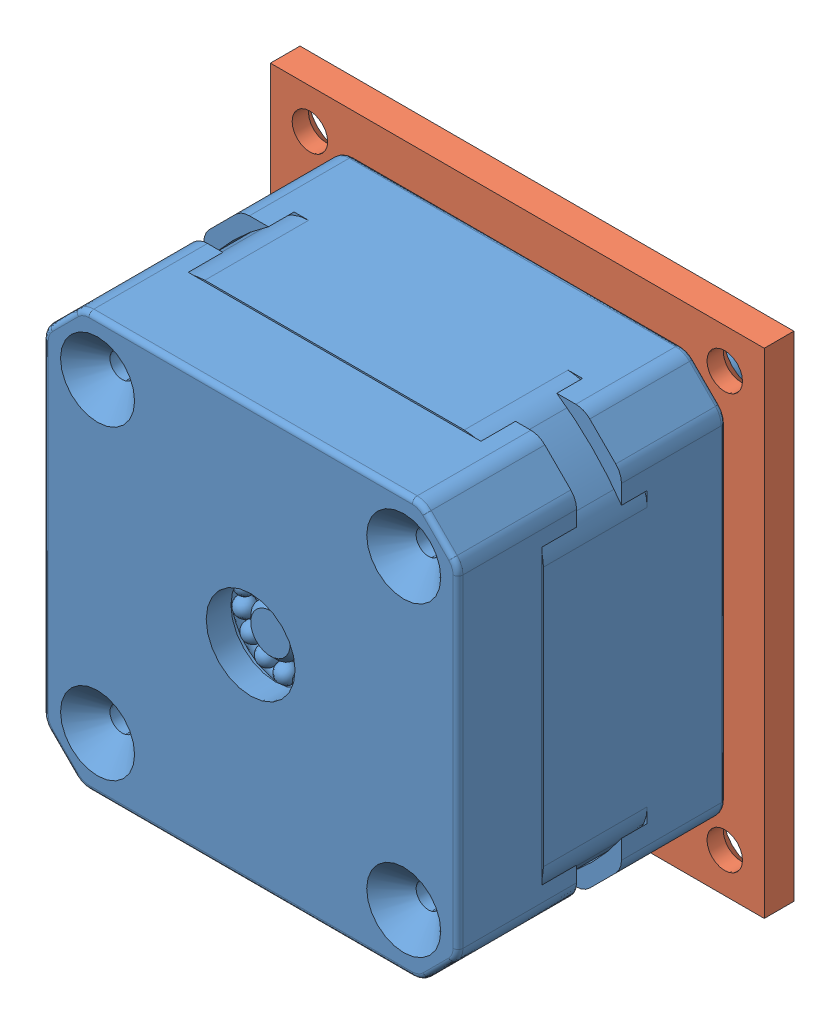
SolidWorks assembly Motor_and_plate, configuration Default. Lengths in mm.
Overall size (50 50 51.3).
2 component instances, 2 part files, 3 mates.
Components (placement in the parent):
- NEMA_17_PHB42S28-406A v2-1: NEMA_17_PHB42S28-406A v2 [Default] at (16.9071 48.8811 -1035.1401) size (42.3 42.3 51.3)
- Plate-1: Plate [Default] at (12.2071 33.8811 36.8599) x (0 -1 0) z (1 0 0) size (50 3 50)
Mates (geometry in assembly coordinates):
- Concentric1: concentric anti-aligned: cylinder of NEMA_17_PHB42S28-406A v2-1 through (12.2071 33.8811 34.8599) axis (0 0 1) radius 11; cylinder of Plate-1 through (12.2071 33.8811 33.8599) axis (0 0 -1) radius 12
- Coincident1: coincident anti-aligned: plane of NEMA_17_PHB42S28-406A v2-1 through (12.2071 33.8811 36.8599) normal (0 0 -1); plane of Plate-1 through (12.2071 33.8811 36.8599) normal (0 0 1)
- Perpendicular1: perpendicular: plane of NEMA_17_PHB42S28-406A v2-1 through (12.2071 12.7311 23.8599) normal (0 -1 0); plane of Plate-1 through (-12.7929 8.8811 33.8599) normal (-1 0 0)
